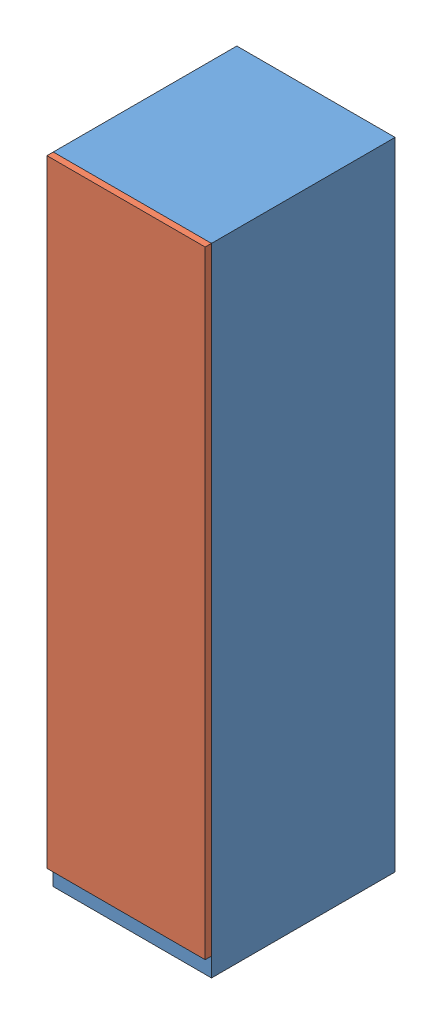
SolidWorks assembly PAX-R, configuration Standard. Lengths in mm.
Overall size (500 2010 600).
5 component instances, 5 part files, 12 mates.
Components (placement in the parent):
- Pax-Korpus-Kleiderschrank-1: Pax-Korpus-Kleiderschrank [Standard] at (-317.8358 -932.7261 1650) size (500 2010 580)
- BALLSTAD-Tür-1: BALLSTAD-Tür [Standard] at (-317.8358 102.2739 1940) size (500 1950 20)
- KOMPLIMENT-Schublade-1: KOMPLIMENT-Schublade [Standard] at (-317.8358 -702.7261 1655) size (480 160 570)
- KOMPLEMENT-Regalbode-2: KOMPLEMENT-Regalbode [Standard] at (-317.8358 -532.7261 1655) size (480 10 570)
- KOMPLEMENT-Netzdrahtkorb-1: KOMPLEMENT-Netzdrahtkorb [Standard] at (-317.8358 -712.7261 1655) size (480 160 570)
Mates (geometry in assembly coordinates):
- Deckungsgleich1: coincident anti-aligned: plane of BALLSTAD-Tür-1 through (-317.8358 102.2739 1940) normal (0 0 -1); plane of Pax-Korpus-Kleiderschrank-1 through (-567.8358 -922.7261 1940) normal (0 0 1)
- Deckungsgleich2: coincident aligned: plane of BALLSTAD-Tür-1 through (-567.8358 -872.7261 1960) normal (-1 0 0); plane of Pax-Korpus-Kleiderschrank-1 through (-567.8358 -922.7261 1940) normal (-1 0 0)
- Deckungsgleich3: coincident aligned: plane of BALLSTAD-Tür-1 through (-567.8358 1077.2739 1960) normal (0 1 0); plane of Pax-Korpus-Kleiderschrank-1 through (-317.8358 1077.2739 1650) normal (0 1 0)
- Deckungsgleich7: coincident anti-aligned: plane of Pax-Korpus-Kleiderschrank-1 through (-557.8358 1067.2739 1370) normal (0 0 1); plane of KOMPLIMENT-Schublade-1 through (-557.8358 -692.7261 1370) normal (0 0 -1)
- Deckungsgleich8: coincident anti-aligned: plane of Pax-Korpus-Kleiderschrank-1 through (-557.8358 1067.2739 1940) normal (1 0 0); plane of KOMPLIMENT-Schublade-1 through (-557.8358 -692.7261 1940) normal (-1 0 0)
- Deckungsgleich10: coincident anti-aligned: plane of Pax-Korpus-Kleiderschrank-1 through (-557.8358 1067.2739 1940) normal (1 0 0); plane of KOMPLEMENT-Regalbode-2 through (-557.8358 -522.7261 1940) normal (-1 0 0)
- Deckungsgleich11: coincident anti-aligned: plane of Pax-Korpus-Kleiderschrank-1 through (-557.8358 1067.2739 1370) normal (0 0 1); plane of KOMPLEMENT-Regalbode-2 through (-557.8358 -522.7261 1370) normal (0 0 -1)
- Abstand3: distance = 10 mm anti-aligned: plane of KOMPLIMENT-Schublade-1 through (-317.8358 -542.7261 1655) normal (0 1 0); plane of KOMPLEMENT-Regalbode-2 through (-317.8358 -532.7261 1655) normal (0 -1 0)
- Deckungsgleich17: coincident anti-aligned: plane of Pax-Korpus-Kleiderschrank-1 through (-317.8358 -872.7261 1650) normal (0 1 0); plane of KOMPLEMENT-Netzdrahtkorb-1 through (-317.8358 -872.7261 1655) normal (0 -1 0)
- Deckungsgleich18: coincident: plane of Pax-Korpus-Kleiderschrank-1 through (-77.8358 1067.2739 1370) normal (-1 0 0); line of KOMPLEMENT-Netzdrahtkorb-1 through (-77.8358 -712.7261 1940) axis (0 0 -1)
- Deckungsgleich19: coincident: plane of Pax-Korpus-Kleiderschrank-1 through (-557.8358 1067.2739 1370) normal (0 0 1); line of KOMPLEMENT-Netzdrahtkorb-1 through (-77.8358 -712.7261 1370) axis (-1 0 0)
- Abstand7: distance = 10 mm anti-aligned: plane of KOMPLEMENT-Netzdrahtkorb-1 through (-317.8358 -712.7261 1655) normal (0 1 0); plane of KOMPLIMENT-Schublade-1 through (-317.8358 -702.7261 1655) normal (0 -1 0)
